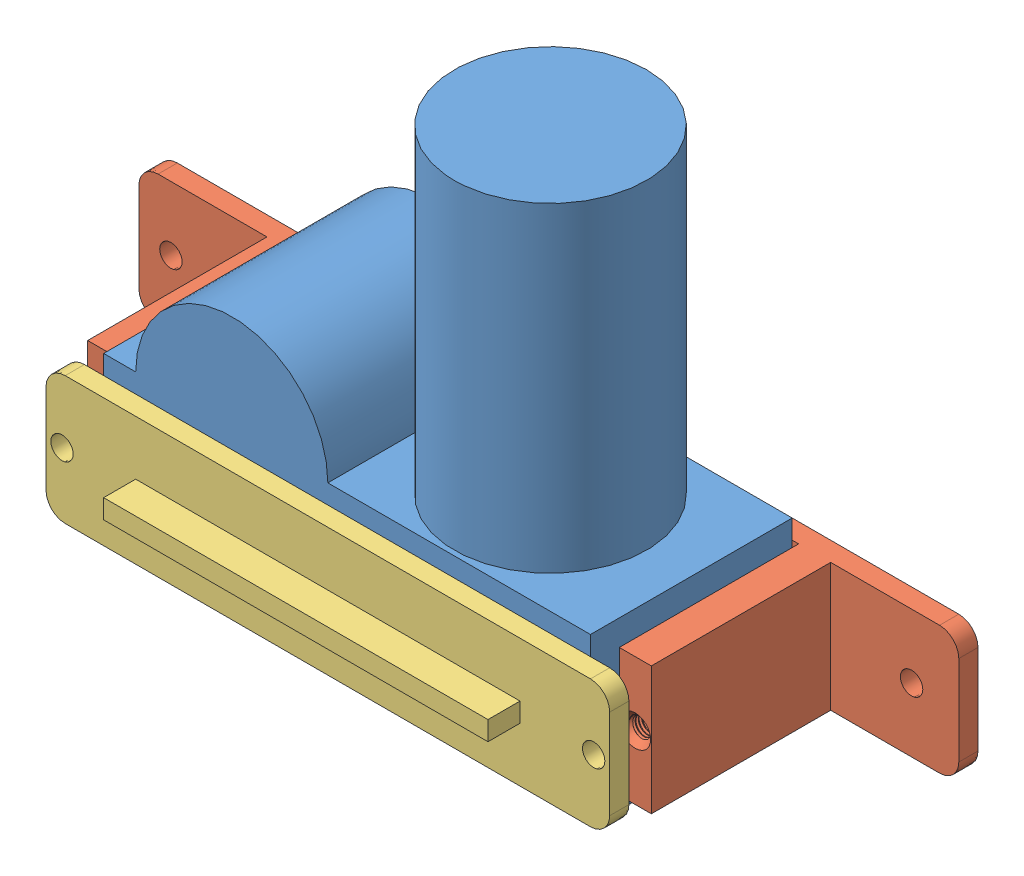
SolidWorks assembly ASM_etincelle, configuration Défaut. Lengths in mm.
Overall size (128 76 42.5).
3 component instances, 3 part files, 6 mates.
Components (placement in the parent):
- module_etincelle-1: module_etincelle [Défaut] at (-50.5718 -35.2237 76) size (76 76 31.5)
- fix_module_etincelle-1: fix_module_etincelle [Défaut] at (-76.5718 -12.2237 73) x (1 0 0) z (0 -1 0) size (128 31 20)
- couvercle_module_etincelle-1: couvercle_module_etincelle [Défaut] at (-56.5718 -32.2237 107.5) size (88 20 8)
Mates (geometry in assembly coordinates):
- Coïncidente1: coincident anti-aligned: plane of module_etincelle-1 through (-30.5718 -9.2237 76) normal (0 0 -1); plane of fix_module_etincelle-1 through (-51.5718 -32.2237 76) normal (0 0 1)
- Distance1: distance = 1 mm anti-aligned: plane of fix_module_etincelle-1 through (-51.5718 -32.2237 104) normal (1 0 0); plane of module_etincelle-1 through (-50.5718 -35.2237 107.5) normal (-1 0 0)
- Distance2: distance = 3 mm aligned: plane of fix_module_etincelle-1 through (-76.5718 -32.2237 73) normal (0 -1 0); plane of module_etincelle-1 through (-50.5718 -35.2237 107.5) normal (0 -1 0)
- Coïncidente4: coincident anti-aligned: plane of module_etincelle-1 through (-30.5718 -9.2237 107.5) normal (0 0 1); plane of couvercle_module_etincelle-1 through (-56.5718 -32.2237 107.5) normal (0 0 -1)
- Coaxiale1: concentric aligned: circle of fix_module_etincelle-1; cylinder of couvercle_module_etincelle-1 through (-54.0718 -22.2237 110.5) axis (0 0 -1) radius 1.75
- Coaxiale2: concentric anti-aligned: circle of fix_module_etincelle-1; circle of couvercle_module_etincelle-1
